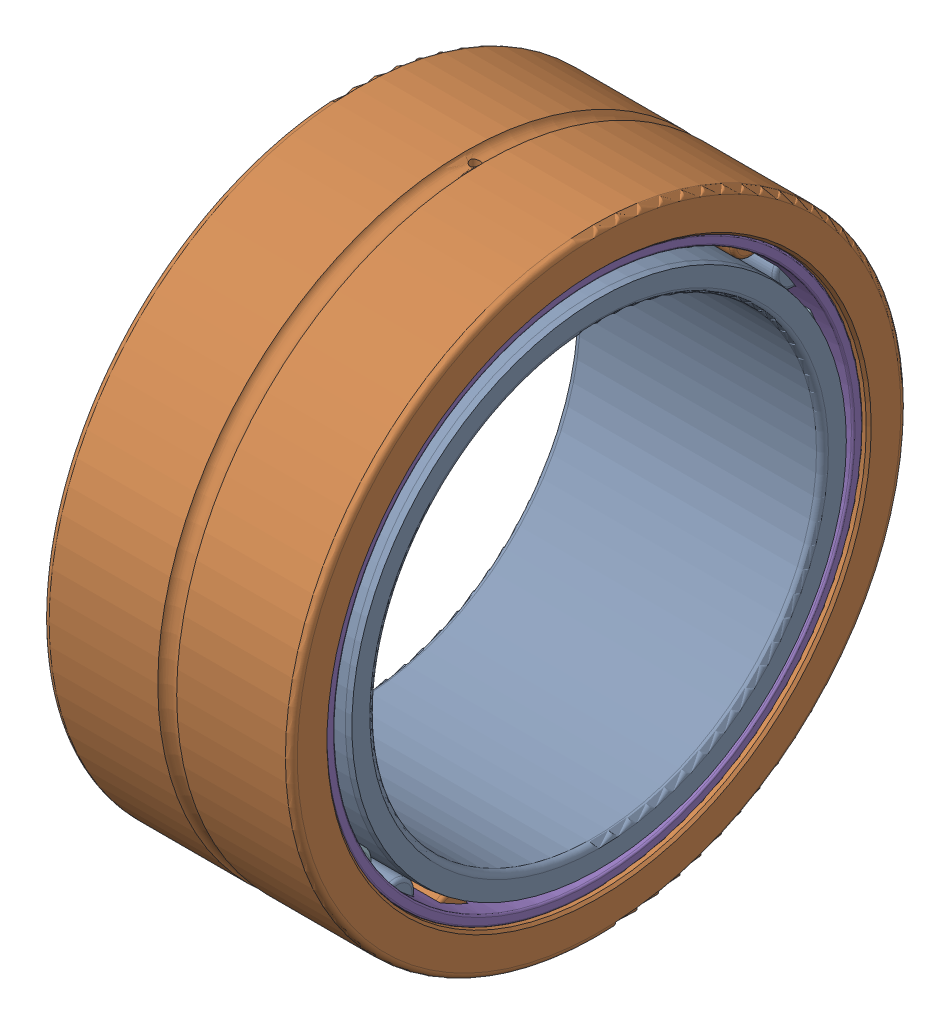
SolidWorks assembly NK50_25RCT+IR45x50x25, configuration Default. Lengths in mm.
Overall size (25 62 62).
29 component instances, 4 part files, 0 mates.
Components (placement in the parent):
- NK50_25RCT+IR45x50x25Inner ring-1: NK50_25RCT+IR45x50x25Inner ring [Default] at origin size (25 50 50)
- NK50_25RCT+IR45x50x25Outer ring-1: NK50_25RCT+IR45x50x25Outer ring [Default] at origin size (25 62 62)
- NK50_25RCT+IR45x50x25 ring-1: NK50_25RCT+IR45x50x25 ring [Default] at (2.5 26.8 0) size (20 3.6 3.6)
- NK50_25RCT+IR45x50x25 ring-2: NK50_25RCT+IR45x50x25 ring [Default] at (2.5 26.0212 6.4137) size (20 3.6 3.6)
- NK50_25RCT+IR45x50x25 ring-3: NK50_25RCT+IR45x50x25 ring [Default] at (2.5 23.7302 12.4546) size (20 3.6 3.6)
- NK50_25RCT+IR45x50x25 ring-4: NK50_25RCT+IR45x50x25 ring [Default] at (2.5 20.0601 17.7717) size (20 3.6 3.6)
- NK50_25RCT+IR45x50x25 ring-5: NK50_25RCT+IR45x50x25 ring [Default] at (2.5 15.2241 22.056) size (20 3.6 3.6)
- NK50_25RCT+IR45x50x25 ring-6: NK50_25RCT+IR45x50x25 ring [Default] at (2.5 9.5034 25.0584) size (20 3.6 3.6)
- NK50_25RCT+IR45x50x25 ring-7: NK50_25RCT+IR45x50x25 ring [Default] at (2.5 3.2304 26.6046) size (20 3.6 3.6)
- NK50_25RCT+IR45x50x25 ring-8: NK50_25RCT+IR45x50x25 ring [Default] at (2.5 -3.2304 26.6046) size (20 3.6 3.6)
- NK50_25RCT+IR45x50x25 ring-9: NK50_25RCT+IR45x50x25 ring [Default] at (2.5 -9.5034 25.0584) size (20 3.6 3.6)
- NK50_25RCT+IR45x50x25 ring-10: NK50_25RCT+IR45x50x25 ring [Default] at (2.5 -15.2241 22.056) size (20 3.6 3.6)
- NK50_25RCT+IR45x50x25 ring-11: NK50_25RCT+IR45x50x25 ring [Default] at (2.5 -20.0601 17.7717) size (20 3.6 3.6)
- NK50_25RCT+IR45x50x25 ring-12: NK50_25RCT+IR45x50x25 ring [Default] at (2.5 -23.7302 12.4546) size (20 3.6 3.6)
- NK50_25RCT+IR45x50x25 ring-13: NK50_25RCT+IR45x50x25 ring [Default] at (2.5 -26.0212 6.4137) size (20 3.6 3.6)
- NK50_25RCT+IR45x50x25 ring-14: NK50_25RCT+IR45x50x25 ring [Default] at (2.5 -26.8 0) size (20 3.6 3.6)
- NK50_25RCT+IR45x50x25 ring-15: NK50_25RCT+IR45x50x25 ring [Default] at (2.5 -26.0212 -6.4137) size (20 3.6 3.6)
- NK50_25RCT+IR45x50x25 ring-16: NK50_25RCT+IR45x50x25 ring [Default] at (2.5 -23.7302 -12.4546) size (20 3.6 3.6)
- NK50_25RCT+IR45x50x25 ring-17: NK50_25RCT+IR45x50x25 ring [Default] at (2.5 -20.0601 -17.7717) size (20 3.6 3.6)
- NK50_25RCT+IR45x50x25 ring-18: NK50_25RCT+IR45x50x25 ring [Default] at (2.5 -15.2241 -22.056) size (20 3.6 3.6)
- NK50_25RCT+IR45x50x25 ring-19: NK50_25RCT+IR45x50x25 ring [Default] at (2.5 -9.5034 -25.0584) size (20 3.6 3.6)
- NK50_25RCT+IR45x50x25 ring-20: NK50_25RCT+IR45x50x25 ring [Default] at (2.5 -3.2304 -26.6046) size (20 3.6 3.6)
- NK50_25RCT+IR45x50x25 ring-21: NK50_25RCT+IR45x50x25 ring [Default] at (2.5 3.2304 -26.6046) size (20 3.6 3.6)
- NK50_25RCT+IR45x50x25 ring-22: NK50_25RCT+IR45x50x25 ring [Default] at (2.5 9.5034 -25.0584) size (20 3.6 3.6)
- NK50_25RCT+IR45x50x25 ring-23: NK50_25RCT+IR45x50x25 ring [Default] at (2.5 15.2241 -22.056) size (20 3.6 3.6)
- NK50_25RCT+IR45x50x25 ring-24: NK50_25RCT+IR45x50x25 ring [Default] at (2.5 20.0601 -17.7717) size (20 3.6 3.6)
- NK50_25RCT+IR45x50x25 ring-25: NK50_25RCT+IR45x50x25 ring [Default] at (2.5 23.7302 -12.4546) size (20 3.6 3.6)
- NK50_25RCT+IR45x50x25 ring-26: NK50_25RCT+IR45x50x25 ring [Default] at (2.5 26.0212 -6.4137) size (20 3.6 3.6)
- NK50_25RCT+IR45x50x25Cage-1: NK50_25RCT+IR45x50x25Cage [Default] at origin size (24 54.22 54.22)
